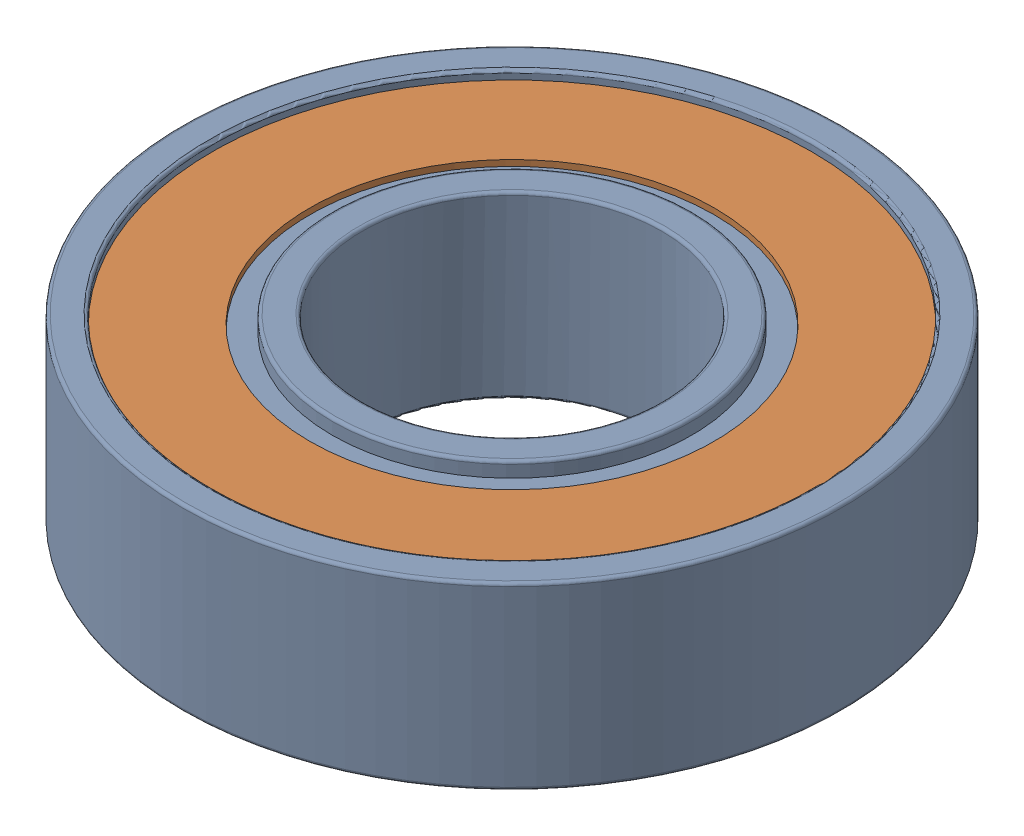
SolidWorks assembly 26, configuration ﾃﾞﾌｫﾙﾄ. Lengths in mm.
Overall size (22 6 22).
3 component instances, 2 part files, 0 mates.
Components (placement in the parent):
- 27-1: 27 [ﾃﾞﾌｫﾙﾄ] at origin size (22 6 22)
- 28-1: 28 [ﾃﾞﾌｫﾙﾄ] at (0 2.5 0) size (20 0.2 20)
- 28-2: 28 [ﾃﾞﾌｫﾙﾄ] at (0 -2.7 0) size (20 0.2 20)
